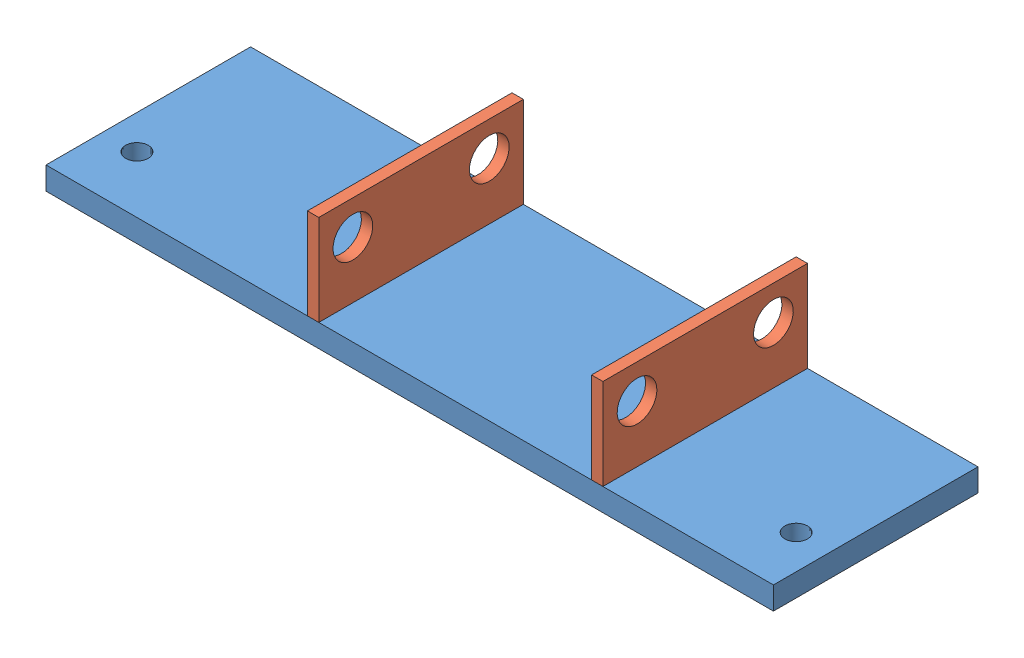
SolidWorks assembly Cam_Support_Ass, configuration Default. Lengths in mm.
Overall size (447.04 89.53 152.4).
3 component instances, 2 part files, 3 mates.
Components (placement in the parent):
- 01-020-00-0-1: 01-020-00-0 [Default] at (-221.5578 -37.3604 106.9552) size (447.04 13.97 152.4)
- Cam Support Tab-1: Cam Support Tab [Default] at (-75.5078 -24.6604 106.9552) x (0 1 0) z (-1 0 0) size (76.2 114.3 6.35)
- Cam Support Tab-2: Cam Support Tab [Default] at (83.2422 -24.6604 106.9552) x (0 1 0) z (-1 0 0) size (76.2 114.3 6.35)
Mates (geometry in assembly coordinates):
- Coincident6: coincident anti-aligned: plane of 01-020-00-0-1 through (-221.5578 -24.6604 -7.3448) normal (0 1 0); plane of Cam Support Tab-1 through (-75.5078 -24.6604 -7.3448) normal (0 -1 0)
- Coincident7: coincident aligned: line of 01-020-00-0-1 through (184.8422 -24.6604 -7.3448) axis (-1 0 0); line of Cam Support Tab-1 through (-69.1578 -24.6604 -7.3448) axis (-1 0 0)
- Distance1: distance = 146.05 mm: line of Cam Support Tab-1 through (-75.5078 -24.6604 -7.3448) axis (0 0 1); line of 01-020-00-0-1 through (-221.5578 -24.6604 -7.3448) axis (0 0 1)
